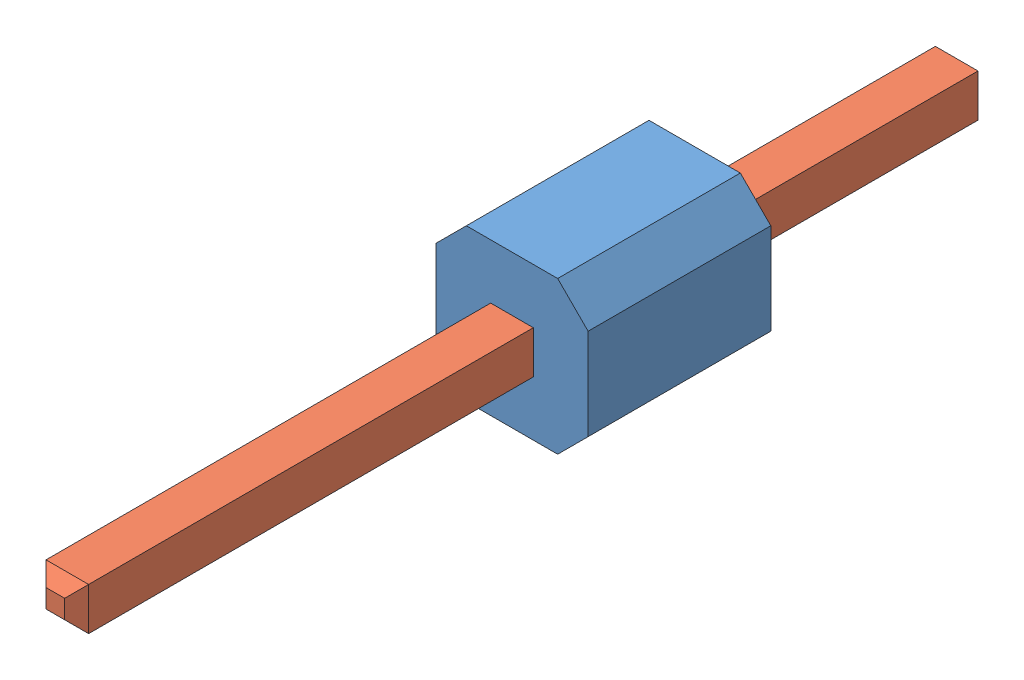
SolidWorks assembly Bloc pin male, configuration Défaut. Lengths in mm.
Overall size (1.27 1.27 7.62).
2 component instances, 2 part files, 3 mates.
Components (placement in the parent):
- Pin_cmi2c_Base-1: Pin_cmi2c_Base [Défaut] at (-0.1729 -0.0306 1.524) size (1.27 1.27 1.52)
- Pin_cmi2c-1: Pin_cmi2c [Défaut] at (-0.1729 0.1472 -0.762) x (1 0 0) z (0 -1 0) size (0.36 7.62 0.36)
Mates (geometry in assembly coordinates):
- Coïncidente1: coincident anti-aligned: plane of Pin_cmi2c_Base-1 through (-0.3507 0.1472 3.048) normal (0 -1 0); plane of Pin_cmi2c-1 through (-0.1729 0.1472 -0.762) normal (0 1 0)
- Coïncidente2: coincident anti-aligned: plane of Pin_cmi2c_Base-1 through (0.0049 0.1472 3.048) normal (-1 0 0); plane of Pin_cmi2c-1 through (0.0049 -0.2084 -0.762) normal (1 0 0)
- Distance1: distance = 3.81 mm aligned: plane of Pin_cmi2c_Base-1 through (-0.1729 -0.0306 3.048) normal (0 0 1); plane of Pin_cmi2c-1 through (-0.3507 -0.2084 6.858) normal (0 0 1)
